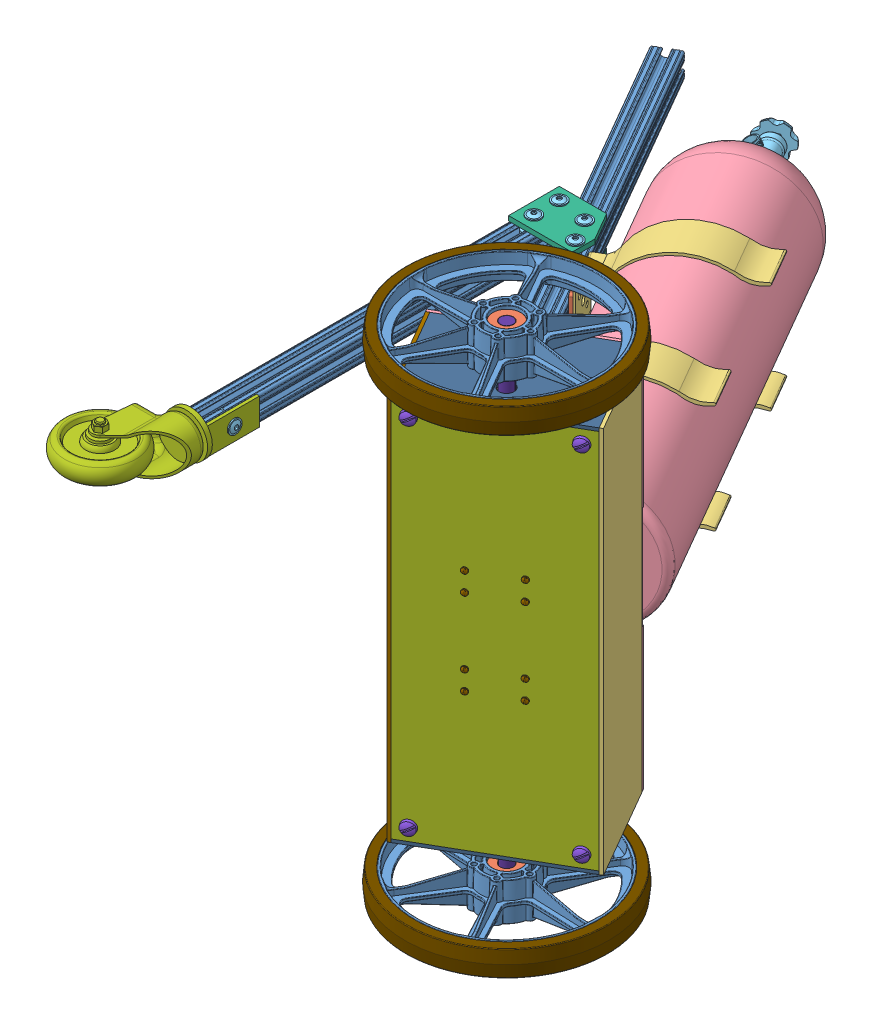
SolidWorks assembly FullAssembly_v3, configuration Default. Lengths in mm.
Overall size (655.19 583.26 804.17).
116 component instances, 27 part files, 137 mates.
Components (placement in the parent):
- 1010 PROFILE-1: 1010 PROFILE [15] at (144.6535 199.9594 480.8949) size (25.4 25.4 381)
- 1010 PROFILE-2: 1010 PROFILE [23.75] at (363.5483 199.9594 443.7256) x (0.86562 0 -0.500701) z (0.500701 0 0.86562) size (25.4 25.4 603.25)
- tankMount_assy-1: tankMount_assy [Default] at (224.6764 199.9594 171.9359) x (0.500701 0 0.86562) z (0 -1 0) size (41.91 148.62 139.7)
  - tankHoler_Mount-1: tankHoler_Mount [Default] at origin size (38.1 3.17 38.1)
  - tankHolder-1: tankHolder [Default] at (19.05 -83.82 0) x (0 0 -1) z (-1 0 0) size (139.7 145.45 41.91)
- tankMount_assy-2: tankMount_assy [Default] at (300.9832 199.9594 303.8564) x (0.500701 0 0.86562) z (0 -1 0) size (41.91 148.62 139.7)
  - tankHoler_Mount-1: tankHoler_Mount [Default] at origin size (38.1 3.17 38.1)
  - tankHolder-1: tankHolder [Default] at (19.05 -83.82 0) x (0 0 -1) z (-1 0 0) size (139.7 145.45 41.91)
- OxTank_Assy-1: OxTank_Assy [Default] at (447.0589 199.9594 392.7938) x (0.86562 0 -0.500701) z (0 1 0) size (133.35 535.03 133.35)
  - M24_OxTank-1: M24_OxTank [Default] at origin size (133.35 486.41 133.35)
  - M24_Valve-1: M24_Valve [Default] at (0 481.33 0) x (-0.429874 0 0.902889) z (-0.902889 0 -0.429874) size (43.69 53.7 33.5)
- 30Deg PN4143-1: 30Deg PN4143 [Default] at (131.9535 217.4346 150.6949) x (0 0 -1) z (1 0 0) size (50.8 4.78 63.5)
- 30Deg PN4143-2: 30Deg PN4143 [Default] at (131.9535 187.2594 150.6949) x (0 0 -1) z (1 0 0) size (50.8 4.78 63.5)
- MotorBox_Assy-1: MotorBox_Assy [Default] at (405.6518 199.9594 541.8792) x (-0.117796 0.990698 0.068137) z (0.500701 0 0.86562) size (541.44 344.28 279.2)
  - 1010 PROFILE-3: 1010 PROFILE [13] at (161.8359 -35.0491 -15.875) x (-0.136082 -0.990698 0) z (0.990698 -0.136082 0) size (25.4 25.4 330.2)
  - MotorBox_Base-1: MotorBox_Base [Default] at (-10.3695 -75.4912 -3.175) x (-0.990698 0.136082 0) z (0.136082 0.990698 0) size (381 3.17 152.4)
  - Motor_Bracket-2: Motor_Bracket [Default] at (-159.2475 -55.0412 -31.75) x (0.136082 0.990698 0) z (-0.990698 0.136082 0) size (88.9 50.8 20.96)
  - Motor_Bracket-3: Motor_Bracket [Default] at (138.5085 -95.9411 -31.75) x (-0.136082 -0.990698 0) z (0.990698 -0.136082 0) size (88.9 50.8 20.96)
  - MotorBox_BackPlate-1: MotorBox_BackPlate [Default] at (0 0 -53.0225) x (0.990698 -0.136082 0) z (0.136082 0.990698 0) size (387.35 106.05 3.17)
  - 1010 PROFILE-5: 1010 PROFILE [4.05] at (-177.8743 11.6136 -3.175) x (0.990698 -0.136082 0) z (0 0 1) size (25.4 25.4 102.87)
  - 1010 PROFILE-6: 1010 PROFILE [4.05] at (174.4178 -36.7773 -3.175) x (0.990698 -0.136082 0) z (0 0 1) size (25.4 25.4 102.87)
  - motorbox_sidePlate-1: motorbox_sidePlate [Default] at (188.7279 -25.9237 0) x (0.990698 -0.136082 0) z (0.136082 0.990698 0) size (3.17 106.05 152.4)
  - motorbox_sidePlate-3: motorbox_sidePlate [Default] at (-191.8733 26.3558 0) x (0.990698 -0.136082 0) z (0.136082 0.990698 0) size (3.17 106.05 152.4)
  - MotorMount_3Dp2-1: MotorMount_3Dp2 [Default] at (17.0936 -79.2635 -3.175) x (-0.136082 -0.990698 0) z (0.990698 -0.136082 0) size (57.15 50.9 30.48)
  - MotorMount_3Dp2-2: MotorMount_3Dp2 [Default] at (-37.8325 -71.7188 -3.175) x (0.136082 0.990698 0) z (-0.990698 0.136082 0) size (57.15 50.9 30.48)
  - 90Deg 2Hole 4108-5: 90Deg 2Hole 4108 [Default] at (-190.2753 0.4978 -55.6714) x (0.990698 -0.136082 0) z (0.136082 0.990698 0) size (25.4 25.4 25.4)
  - 90Deg 2Hole 4108-6: 90Deg 2Hole 4108 [Default] at (186.8188 -25.6615 -55.6714) x (-0.990698 0.136082 0) z (-0.136082 -0.990698 0) size (25.4 25.4 25.4)
  - Motor_Coupler_WheelAssy-1: Motor_Coupler_WheelAssy [Default] at (82.653 -91.6609 -43.1023) x (0.117796 0.857568 -0.500701) z (-0.990698 0.136082 0) size (204.35 204.35 248.71)
    - Motor-1: Motor [Default] at (-2.7115 -11.3995 12.6743) size (45.1 45.1 159.4)
    - Coupler_Assembly-1: Coupler_Assembly [Default] at (-18.5282 -16.0979 -94.9854) x (0.697262 -0.716816 0) z (0 0 1) size (25.52 25.52 28.68)
      - CouplingCenter_59985K630-1: CouplingCenter_59985K630 [59985K63] at (7.6605 14.6137 19.5344) size (25.4 25.4 7.92)
      - halfInCoupling_59985K190-1: halfInCoupling_59985K190 [59985K19] at (7.6605 14.6137 19.4804) size (25.52 25.52 14.06)
      - 10mmCoupling_59985K305-1: 10mmCoupling_59985K305 [59985K305] at (7.6605 14.6137 19.5884) x (0 1 0) z (0 0 -1) size (25.52 25.52 14.06)
    - HalfInch_Shaft-1: HalfInch_Shaft [Default] at (-2.7115 -11.3995 -156.5786) size (12.7 12.7 76.2)
    - 8inWheel_AndyMarkAlternative-1: 8inWheel_AndyMarkAlternative [Default] at (-2.7115 -11.3995 -153.4798) size (204.35 204.35 38.11)
      - 2010 8 tread-1: 2010 8 tread [Default] at (0 0 12.7) size (204.35 204.35 25.4)
      - 2010 8 hub-1: 2010 8 hub [Default] at origin size (190.5 190.5 38.11)
      - r8 bearing-1: r8 bearing [Default] at (0 0 -3.0988) x (-0.726935 0.686706 0) z (0 0 1) size (28.57 28.57 6.35)
      - r8 bearing-2: r8 bearing [Default] at (0 0 28.575) x (0.399336 0.916804 0) z (0 0 -1) size (28.57 28.57 6.35)
  - Motor_Coupler_WheelAssy-2: Motor_Coupler_WheelAssy [Default] at (-104.2482 -65.5549 -20.405) x (0.120301 0.875807 0.467429) z (0.990698 -0.136082 0) size (204.35 204.35 248.71)
    - Motor-1: Motor [Default] at (-2.7115 -11.3995 12.6743) size (45.1 45.1 159.4)
    - Coupler_Assembly-1: Coupler_Assembly [Default] at (-18.5282 -16.0979 -94.9854) x (0.697262 -0.716816 0) z (0 0 1) size (25.52 25.52 28.68)
      - CouplingCenter_59985K630-1: CouplingCenter_59985K630 [59985K63] at (7.6605 14.6137 19.5344) size (25.4 25.4 7.92)
      - halfInCoupling_59985K190-1: halfInCoupling_59985K190 [59985K19] at (7.6605 14.6137 19.4804) size (25.52 25.52 14.06)
      - 10mmCoupling_59985K305-1: 10mmCoupling_59985K305 [59985K305] at (7.6605 14.6137 19.5884) x (0 1 0) z (0 0 -1) size (25.52 25.52 14.06)
    - HalfInch_Shaft-1: HalfInch_Shaft [Default] at (-2.7115 -11.3995 -156.5786) size (12.7 12.7 76.2)
    - 8inWheel_AndyMarkAlternative-1: 8inWheel_AndyMarkAlternative [Default] at (-2.7115 -11.3995 -153.4798) size (204.35 204.35 38.11)
      - 2010 8 tread-1: 2010 8 tread [Default] at (0 0 12.7) size (204.35 204.35 25.4)
      - 2010 8 hub-1: 2010 8 hub [Default] at origin size (190.5 190.5 38.11)
      - r8 bearing-1: r8 bearing [Default] at (0 0 -3.0988) x (-0.726935 0.686706 0) z (0 0 1) size (28.57 28.57 6.35)
      - r8 bearing-2: r8 bearing [Default] at (0 0 28.575) x (0.399336 0.916804 0) z (0 0 -1) size (28.57 28.57 6.35)
  - 1010 PROFILE-7: 1010 PROFILE [4.05] at (157.1353 -162.5959 -3.175) x (-0.136082 -0.990698 0) z (0 0 1) size (25.4 25.4 102.87)
  - 1010 PROFILE-8: 1010 PROFILE [4.05] at (-195.1567 -114.205 -3.175) x (-0.136082 -0.990698 0) z (0 0 1) size (25.4 25.4 102.87)
  - MotorBox_FrontPlate-1: MotorBox_FrontPlate [Default] at (-21.171 -154.1278 -53.0225) x (0.990698 -0.136082 0) z (0.136082 0.990698 0) size (387.35 106.05 3.17)
  - MotorBox_TopPlate-1: MotorBox_TopPlate [Default] at (-10.3695 -75.4912 -109.22) x (-0.990698 0.136082 0) z (0 0 1) size (387.35 158.75 3.17)
  - Tnut_47065T142-1: Tnut_47065T142 [47065T142] at (177.5632 -37.2094 -52.959) x (-0.136082 -0.990698 0) z (0 0 1) size (13.84 15.48 25.4)
  - Tnut_47065T142-2: Tnut_47065T142 [47065T142] at (160.2808 -163.028 -52.959) x (-0.136082 -0.990698 0) z (0 0 1) size (13.84 15.48 25.4)
  - Tnut_47065T142-3: Tnut_47065T142 [47065T142] at (-181.0197 12.0457 -52.959) x (0.136082 0.990698 0) z (0 0 1) size (13.84 15.48 25.4)
  - Tnut_47065T142-4: Tnut_47065T142 [47065T142] at (-198.3022 -113.7729 -52.959) x (0.136082 0.990698 0) z (0 0 1) size (13.84 15.48 25.4)
  - Tnut_47065T142-5: Tnut_47065T142 [47065T142] at (-152.7105 8.1571 -19.05) x (0.136082 0.990698 0) z (-0.990698 0.136082 0) size (13.84 15.48 25.4)
  - Tnut_47065T142-6: Tnut_47065T142 [47065T142] at (-174.7288 11.1815 -41.275) x (-0.136082 -0.990698 0) z (0 0 1) size (13.84 15.48 25.4)
  - Tnut_47065T142-7: Tnut_47065T142 [47065T142] at (171.2723 -36.3453 -41.275) x (-0.135988 -0.990011 0.037224) z (-0.005066 -0.036878 -0.999307) size (13.84 15.48 25.4)
  - Tnut_47065T142-8: Tnut_47065T142 [47065T142] at (149.2541 -33.3208 -19.05) x (0.136082 0.990698 0) z (-0.990698 0.136082 0) size (13.84 15.48 25.4)
- Tbracket_47065T182-1: Tbracket_47065T182 [47065T182] at (335.7146 174.5594 430.4823) x (0 1 0) z (-0.86562 0 0.500701) size (76.2 76.2 4.76)
- 1010 PROFILE-3: 1010 PROFILE [13] at (369.9072 365.0594 454.7189) x (0.86562 0 -0.500701) z (0 1 0) size (25.4 25.4 330.2)
- 90Deg 2Hole 4108-1: 90Deg 2Hole 4108 [Default] at (364.3079 239.7558 470.4032) x (-0.500701 0 -0.86562) z (0.86562 0 -0.500701) size (25.4 25.4 25.4)
- 90Deg 2Hole 4108-2: 90Deg 2Hole 4108 [Default] at (386.2947 160.163 457.6854) x (-0.500701 0 -0.86562) z (-0.86562 0 0.500701) size (25.4 25.4 25.4)
- Caster_2399T600-1: Caster_2399T600 [2399T6] at (143.8597 200.7531 491.2136) x (-1 0 0) z (0 -1 0) size (91.62 149.22 46.44)
- Tbracket_47065T182-2: Tbracket_47065T182 [47065T182] at (361.8239 174.5594 415.3799) x (0 1 0) z (-0.86562 0 0.500701) size (76.2 76.2 4.76)
- 90Deg 2Hole 4108-3: 90Deg 2Hole 4108 [Default] at (375.5065 61.9558 439.0347) x (0.500701 0 0.86562) z (-0.86562 0 0.500701) size (25.4 25.4 25.4)
- 90Deg 2Hole 4108-4: 90Deg 2Hole 4108 [Default] at (353.5198 337.963 451.7525) x (0.500701 0 0.86562) z (0.86562 0 -0.500701) size (25.4 25.4 25.4)
- Tnut_47065T142-1: Tnut_47065T142 [47065T142] at (365.7847 174.5594 457.1035) x (0.085321 0.985374 0.147505) z (0.493378 -0.170404 0.85296) size (13.84 15.48 25.4)
- Tnut_47065T142-2: Tnut_47065T142 [47065T142] at (353.0669 199.9594 435.1168) x (0.180474 0.932781 0.312007) z (0.467044 -0.360443 0.807434) size (13.84 15.48 25.4)
- Tnut_47065T142-3: Tnut_47065T142 [47065T142] at (365.7847 225.3594 457.1035) x (0.427935 0.51917 0.739821) z (0.259949 -0.854671 0.449404) size (13.84 15.48 25.4)
- Tnut_47065T142-4: Tnut_47065T142 [47065T142] at (340.3491 199.9594 413.13) x (0.309252 0.786462 0.534641) z (0.393782 -0.617639 0.680778) size (13.84 15.48 25.4)
- Tnut_47065T142-5: Tnut_47065T142 [47065T142] at (365.7847 199.9594 457.1035) x (0.149627 0.954305 0.258677) z (0.477821 -0.298834 0.826066) size (13.84 15.48 25.4)
- Tnut_47065T142-6: Tnut_47065T142 [47065T142] at (357.1894 196.7844 432.7322) x (-0.837169 0 -0.546944) z (-0.546944 0 0.837169) size (13.84 15.48 25.4)
- Tnut_47065T142-7: Tnut_47065T142 [47065T142] at (368.3175 174.5594 451.9706) x (0.749299 0.500701 -0.433417) z (-0.433417 0.86562 0.250701) size (13.84 15.48 25.4)
- Tnut_47065T142-8: Tnut_47065T142 [47065T142] at (368.3175 225.3594 451.9706) x (0.749299 0.500701 -0.433417) z (-0.433417 0.86562 0.250701) size (13.84 15.48 25.4)
- Tnut_47065T142-9: Tnut_47065T142 [47065T142] at (357.1894 203.1344 432.7322) size (13.84 15.48 25.4)
- Tnut_47065T142-10: Tnut_47065T142 [47065T142] at (348.5941 199.9594 408.3608) x (0.250701 -0.86562 0.433417) z (0.433417 0.500701 0.749299) size (13.84 15.48 25.4)
- Tnut_47065T142-11: Tnut_47065T142 [47065T142] at (361.312 199.9594 430.3476) x (0.250701 -0.86562 0.433417) z (0.433417 0.500701 0.749299) size (13.84 15.48 25.4)
- Tnut_47065T142-12: Tnut_47065T142 [47065T142] at (374.0298 225.3594 452.3344) x (0.250701 -0.86562 0.433417) z (0.433417 0.500701 0.749299) size (13.84 15.48 25.4)
- Tnut_47065T142-13: Tnut_47065T142 [47065T142] at (374.0298 174.5594 452.3344) x (0.250701 -0.86562 0.433417) z (0.433417 0.500701 0.749299) size (13.84 15.48 25.4)
- Tnut_47065T142-14: Tnut_47065T142 [47065T142] at (374.0298 199.9594 452.3344) x (0.201827 -0.915161 0.348922) z (0.458222 0.403089 0.792182) size (13.84 15.48 25.4)
- Tnut_47065T142-15: Tnut_47065T142 [47065T142] at (144.6535 204.7346 112.5949) x (-0.997896 0 0.06484) z (-0.06484 0 -0.997896) size (13.84 15.48 25.4)
- Tnut_47065T142-16: Tnut_47065T142 [47065T142] at (144.6535 204.7346 137.9949) x (-0.997896 0 0.06484) z (-0.06484 0 -0.997896) size (13.84 15.48 25.4)
- Tnut_47065T142-17: Tnut_47065T142 [47065T142] at (174.6966 204.7346 117.2355) x (-0.997896 0 0.06484) z (-0.06484 0 -0.997896) size (13.84 15.48 25.4)
- Tnut_47065T142-18: Tnut_47065T142 [47065T142] at (187.4067 204.7346 139.209) x (-0.997896 0 0.06484) z (-0.06484 0 -0.997896) size (13.84 15.48 25.4)
- Tnut_47065T142-19: Tnut_47065T142 [47065T142] at (144.6535 195.1842 112.5949) x (-0.799944 0 -0.600075) z (-0.600075 0 0.799944) size (13.84 15.48 25.4)
- Tnut_47065T142-20: Tnut_47065T142 [47065T142] at (144.6535 195.1842 137.9949) x (-0.799944 0 -0.600075) z (-0.600075 0 0.799944) size (13.84 15.48 25.4)
- Tnut_47065T142-21: Tnut_47065T142 [47065T142] at (174.6966 195.1842 117.2355) x (-0.799944 0 -0.600075) z (-0.600075 0 0.799944) size (13.84 15.48 25.4)
- Tnut_47065T142-22: Tnut_47065T142 [47065T142] at (187.4067 195.1842 139.209) x (-0.799944 0 -0.600075) z (-0.600075 0 0.799944) size (13.84 15.48 25.4)
- Tnut_47065T142-24: Tnut_47065T142 [47065T142] at (143.8597 196.7844 436.4449) x (0.799944 0 0.600075) z (0.600075 0 -0.799944) size (13.84 15.48 25.4)
- Tnut_47065T142-25: Tnut_47065T142 [47065T142] at (143.8597 196.7844 468.1949) x (0.799944 0 0.600075) z (0.600075 0 -0.799944) size (13.84 15.48 25.4)
- Tnut_47065T142-26: Tnut_47065T142 [47065T142] at (147.8285 200.7531 453.9074) x (0 0.440972 -0.897521) z (0 -0.897521 -0.440972) size (13.84 15.48 25.4)
- Tnut_47065T142-27: Tnut_47065T142 [47065T142] at (382.625 25.3344 476.7057) x (0.997896 0 -0.06484) z (0.06484 0 0.997896) size (13.84 15.48 25.4)
- Tnut_47065T142-28: Tnut_47065T142 [47065T142] at (371.497 47.5594 457.4673) x (-0.862672 -0.08247 0.498995) z (-0.071388 0.996594 0.041293) size (13.84 15.48 25.4)
- Tnut_47065T142-29: Tnut_47065T142 [47065T142] at (382.625 374.5844 476.7057) x (-0.799944 0 -0.600075) z (-0.600075 0 0.799944) size (13.84 15.48 25.4)
- Tnut_47065T142-31: Tnut_47065T142 [47065T142] at (371.497 352.3594 457.4673) x (-0.862672 -0.08247 0.498995) z (-0.071388 0.996594 0.041293) size (13.84 15.48 25.4)
- 0.25-20-94690A542-2: 0.25-20-94690A542 [94690A542] at (471.8924 377.7594 377.3882) x (-0.86562 0 0.500701) z (-0.500701 0 -0.86562) size (13.33 13.33 30.02)
- 0.25-20-94690A542-3: 0.25-20-94690A542 [94690A542] at (361.9586 377.7594 440.9772) x (-0.86562 0 0.500701) z (-0.500701 0 -0.86562) size (13.33 13.33 30.02)
- 0.25-20-94690A542-4: 0.25-20-94690A542 [94690A542] at (361.9586 22.1594 440.9772) x (-0.86562 0 0.500701) z (-0.500701 0 -0.86562) size (13.33 13.33 30.02)
- 0.25-20-94690A542-6: 0.25-20-94690A542 [94690A542] at (471.8924 22.1594 377.3882) x (-0.86562 0 0.500701) z (-0.500701 0 -0.86562) size (13.33 13.33 30.02)
- 0.25-20-94690A542-7: 0.25-20-94690A542 [94690A542] at (526.579 377.7594 471.9313) x (-0.74152 -0.515925 0.428917) z (0.500701 0 0.86562) size (13.33 13.33 30.02)
- 0.25-20-94690A542-8: 0.25-20-94690A542 [94690A542] at (416.6452 377.7594 535.5203) x (-0.74152 -0.515925 0.428917) z (0.500701 0 0.86562) size (13.33 13.33 30.02)
- 0.25-20-94690A542-9: 0.25-20-94690A542 [94690A542] at (526.579 22.1594 471.9313) x (-0.74152 -0.515925 0.428917) z (0.500701 0 0.86562) size (13.33 13.33 30.02)
- 0.25-20-94690A542-12: 0.25-20-94690A542 [94690A542] at (416.6452 22.1594 535.5203) x (-0.74152 -0.515925 0.428917) z (0.500701 0 0.86562) size (13.33 13.33 30.02)
- 4_40-90277A108-1: 4_40-90277A108 [90277A108] at (490.8505 252.4453 492.5977) x (-0.216021 -0.96836 0.124953) z (0.500701 0 0.86562) size (5.97 5.97 11.45)
- 4_40-90277A108-2: 4_40-90277A108 [90277A108] at (452.2637 252.2834 514.9174) x (-0.216021 -0.96836 0.124953) z (0.500701 0 0.86562) size (5.97 5.97 11.45)
- 4_40-90277A108-3: 4_40-90277A108 [90277A108] at (452.2637 233.2334 514.9174) x (-0.216021 -0.96836 0.124953) z (0.500701 0 0.86562) size (5.97 5.97 11.45)
- 4_40-90277A108-4: 4_40-90277A108 [90277A108] at (490.7405 233.2334 492.6613) x (-0.216021 -0.96836 0.124953) z (0.500701 0 0.86562) size (5.97 5.97 11.45)
- 4_40-90277A108-5: 4_40-90277A108 [90277A108] at (490.7405 166.6854 492.6613) x (-0.216021 -0.96836 0.124953) z (0.500701 0 0.86562) size (5.97 5.97 11.45)
- 4_40-90277A108-6: 4_40-90277A108 [90277A108] at (490.7405 147.6354 492.6613) x (-0.216021 -0.96836 0.124953) z (0.500701 0 0.86562) size (5.97 5.97 11.45)
- 4_40-90277A108-8: 4_40-90277A108 [90277A108] at (452.2637 166.6854 514.9174) x (-0.216021 -0.96836 0.124953) z (0.500701 0 0.86562) size (5.97 5.97 11.45)
- 4_40-90277A108-9: 4_40-90277A108 [90277A108] at (452.2637 147.6354 514.9174) x (-0.216021 -0.96836 0.124953) z (0.500701 0 0.86562) size (5.97 5.97 11.45)
Mates (geometry in assembly coordinates):
- Coincident1: coincident aligned: plane of 1010 PROFILE-1 through (144.6535 199.9594 480.8949) normal (0 1 0); plane of 1010 PROFILE-2
- Coincident2: coincident anti-aligned: plane of 1010 PROFILE-2; plane of tankMount_assy-1/tankHoler_Mount-1 through (224.6764 199.9594 171.9359) normal (0 -1 0)
- Coincident3: coincident anti-aligned: plane of 1010 PROFILE-2 through (72.4939 190.409 -84.8188) normal (0.86562 0 -0.500701); plane of tankMount_assy-1/tankHoler_Mount-1 through (221.9281 199.9594 173.5256) normal (-0.86562 0 0.500701)
- Distance1: distance = 279.4 mm aligned: plane of 1010 PROFILE-2 through (60.0209 192.2886 -77.6041) normal (-0.500701 0 -0.86562); plane of tankMount_assy-1/tankHoler_Mount-1 through (212.3897 219.0094 157.0355) normal (-0.500701 0 -0.86562)
- Coincident4: coincident anti-aligned: plane of 1010 PROFILE-2; plane of tankMount_assy-2/tankHoler_Mount-1 through (300.9832 199.9594 303.8564) normal (0 -1 0)
- Coincident5: coincident anti-aligned: plane of 1010 PROFILE-2 through (72.4939 190.409 -84.8188) normal (0.86562 0 -0.500701); plane of tankMount_assy-2/tankHoler_Mount-1 through (298.2349 199.9594 305.4461) normal (-0.86562 0 0.500701)
- Distance2: distance = 431.8 mm aligned: plane of tankMount_assy-2/tankHoler_Mount-1 through (288.6965 219.0094 288.9561) normal (-0.500701 0 -0.86562); plane of 1010 PROFILE-2 through (60.0209 192.2886 -77.6041) normal (-0.500701 0 -0.86562)
- Parallel2: parallel anti-aligned: plane of 1010 PROFILE-2 through (60.0209 192.2886 -77.6041) normal (-0.500701 0 -0.86562); plane of OxTank_Assy-1/M24_OxTank-1 through (447.0589 199.9594 392.7938) normal (0.500701 0 0.86562)
- Coincident7: coincident aligned: plane of 1010 PROFILE-2; plane of OxTank_Assy-1/M24_OxTank-1 through (447.0589 199.9594 392.7938) normal (0 1 0)
- Distance3: distance = 12.7 mm aligned: plane of 30Deg PN4143-1 through (131.9535 217.4346 150.6949) normal (1 0 0); plane of 1010 PROFILE-1 through (144.6535 199.9594 480.8949) normal (1 0 0)
- Coincident9: coincident aligned: plane of 1010 PROFILE-1 through (142.9442 192.2886 99.8949) normal (0 0 -1); plane of 30Deg PN4143-1 through (179.3499 212.6594 99.8949) normal (0 0 -1)
- Coincident10: coincident anti-aligned: plane of 1010 PROFILE-1 through (138.3204 212.6594 99.8949) normal (0 1 0); plane of 30Deg PN4143-1 through (131.9535 212.6594 150.6949) normal (0 -1 0)
- Distance4: distance = 12.7 mm aligned: plane of 1010 PROFILE-1 through (144.6535 199.9594 480.8949) normal (1 0 0); plane of 30Deg PN4143-2 through (131.9535 187.2594 150.6949) normal (1 0 0)
- Coincident12: coincident aligned: plane of 1010 PROFILE-1 through (142.9442 192.2886 99.8949) normal (0 0 -1); plane of 30Deg PN4143-2 through (179.3499 182.4842 99.8949) normal (0 0 -1)
- Coincident13: coincident anti-aligned: plane of 1010 PROFILE-1 through (135.1031 187.2594 99.8949) normal (0 -1 0); plane of 30Deg PN4143-2 through (131.9535 187.2594 150.6949) normal (0 1 0)
- Coincident16: coincident anti-aligned: plane of 1010 PROFILE-2 through (363.5483 199.9594 443.7256) normal (0.86562 0 -0.500701); plane of 30Deg PN4143-2
- Parallel7: parallel anti-aligned: plane of 1010 PROFILE-2 through (363.5483 199.9594 443.7256) normal (0.500701 0 0.86562); plane of MotorBox_Assy-1/MotorBox_BackPlate-1 through (349.8066 6.2844 451.6742) normal (-0.500701 0 -0.86562)
- Coincident25: coincident aligned: plane of 1010 PROFILE-2; plane of OxTank_Assy-1/M24_OxTank-1 through (447.0589 199.9594 392.7938) normal (0 1 0)
- Distance8: distance = 81.915 mm anti-aligned: plane of tankMount_assy-1/tankHoler_Mount-1; plane of OxTank_Assy-1/M24_OxTank-1
- Coincident27: coincident anti-aligned: plane of 1010 PROFILE-2; plane of Tbracket_47065T182-1
- Coincident28: coincident anti-aligned: plane of 1010 PROFILE-2 through (50.5071 209.5098 -72.101) normal (-0.86562 0 0.500701); plane of Tbracket_47065T182-1 through (327.1193 187.2594 406.111) normal (0.86562 0 -0.500701)
- Distance9: distance = 12.7 mm anti-aligned: plane of 1010 PROFILE-3; plane of Tbracket_47065T182-1 through (365.2728 199.9594 472.0712) normal (0.500701 0 0.86562)
- Coincident30: coincident anti-aligned: plane of Tbracket_47065T182-1 through (327.1193 187.2594 406.111) normal (0.86562 0 -0.500701); plane of 1010 PROFILE-3 through (362.0848 34.8594 466.5599) normal (-0.86562 0 0.500701)
- Distance10: distance = 165.1 mm anti-aligned: plane of 1010 PROFILE-3 through (369.9072 365.0594 454.7189) normal (0 1 0); plane of Tbracket_47065T182-1
- Distance11: distance = 25.4 mm aligned: plane of 1010 PROFILE-2 through (362.0688 192.2886 444.5814) normal (0.500701 0 0.86562); plane of Tbracket_47065T182-1 through (365.2728 199.9594 472.0712) normal (0.500701 0 0.86562)
- Coincident33: coincident anti-aligned: plane of 1010 PROFILE-3 through (371.8154 34.8594 438.9437) normal (-0.500701 0 -0.86562); plane of 90Deg 2Hole 4108-1 through (374.5417 238.0594 437.3667) normal (0.500701 0 0.86562)
- Coincident34: coincident anti-aligned: plane of 1010 PROFILE-2 through (69.7675 212.6594 -83.2418) normal (0 1 0); plane of 90Deg 2Hole 4108-1 through (374.5417 212.6594 437.3667) normal (0 -1 0)
- Coincident35: coincident aligned: plane of 1010 PROFILE-3 through (377.7296 34.8594 442.878) normal (0.86562 0 -0.500701); plane of 90Deg 2Hole 4108-1 through (374.5417 234.8844 437.3667) normal (0.86562 0 -0.500701)
- Coincident36: coincident anti-aligned: plane of 1010 PROFILE-2 through (66.9826 187.2594 -81.6309) normal (0 -1 0); plane of 90Deg 2Hole 4108-2 through (352.555 187.2594 450.0845) normal (0 1 0)
- Coincident37: coincident anti-aligned: plane of 1010 PROFILE-3 through (371.8154 34.8594 438.9437) normal (-0.500701 0 -0.86562); plane of 90Deg 2Hole 4108-2 through (352.555 161.8594 450.0845) normal (0.500701 0 0.86562)
- Coincident38: coincident aligned: plane of 1010 PROFILE-3 through (377.7296 34.8594 442.878) normal (0.86562 0 -0.500701); plane of 90Deg 2Hole 4108-2 through (374.5417 165.0344 437.3667) normal (0.86562 0 -0.500701)
- Coincident41: coincident aligned: plane of MotorBox_Assy-1/1010 PROFILE-6 through (370.1883 376.0501 439.8848) normal (-0.500701 0 -0.86562); plane of 1010 PROFILE-3 through (358.0663 34.8594 446.8965) normal (-0.500701 0 -0.86562)
- Coincident42: coincident anti-aligned: plane of MotorBox_Assy-1/1010 PROFILE-6 through (355.2813 365.0594 448.5075) normal (0 -1 0); plane of 1010 PROFILE-3 through (372.2685 365.0594 462.2148) normal (0 1 0)
- Coincident43: coincident aligned: plane of MotorBox_Assy-1/1010 PROFILE-6 through (352.555 371.4263 450.0845) normal (-0.86562 0 0.500701); plane of 1010 PROFILE-3 through (354.132 34.8594 452.8108) normal (-0.86562 0 0.500701)
- Coincident44: coincident anti-aligned: plane of 1010 PROFILE-1 through (142.9442 192.2886 480.8949) normal (0 0 1); plane of Caster_2399T600-1 through (165.6332 200.7531 480.8949) normal (0 0 -1)
- Coincident45: coincident anti-aligned: plane of 1010 PROFILE-1 through (157.3535 206.2925 99.8949) normal (1 0 0); plane of Caster_2399T600-1 through (157.3535 214.2469 428.5074) normal (-1 0 0)
- Coincident46: coincident anti-aligned: plane of 1010 PROFILE-1 through (135.1031 187.2594 99.8949) normal (0 -1 0); plane of Caster_2399T600-1 through (157.3535 187.2594 401.3338) normal (0 1 0)
- Distance15: distance = 96.8375 mm aligned: plane of MotorBox_Assy-1/Motor_Coupler_WheelAssy-1/8inWheel_AndyMarkAlternative-1/2010 8 hub-1; plane of Caster_2399T600-1 through (165.6332 200.7531 480.8949) normal (0 0 -1)
- Coincident47: coincident anti-aligned: plane of 1010 PROFILE-2 through (72.4939 206.2925 -84.8188) normal (0.86562 0 -0.500701); plane of Tbracket_47065T182-2 through (349.1061 187.2594 393.3932) normal (-0.86562 0 0.500701)
- Coincident49: coincident anti-aligned: plane of 1010 PROFILE-2; plane of Tbracket_47065T182-2
- Coincident50: coincident aligned: plane of 1010 PROFILE-3 through (381.7482 34.8594 462.5413) normal (0.500701 0 0.86562); plane of Tbracket_47065T182-2 through (391.382 199.9594 456.9688) normal (0.500701 0 0.86562)
- Coincident51: coincident anti-aligned: plane of 1010 PROFILE-3 through (367.9991 34.8594 470.4942) normal (0.500701 0 0.86562); plane of 90Deg 2Hole 4108-3 through (365.2728 60.2594 472.0712) normal (-0.500701 0 -0.86562)
- Coincident52: coincident anti-aligned: plane of MotorBox_Assy-1/1010 PROFILE-5 through (371.8154 34.8594 438.9437) normal (0 1 0); plane of 90Deg 2Hole 4108-3 through (365.2728 34.8594 472.0712) normal (0 -1 0)
- Coincident53: coincident aligned: plane of 1010 PROFILE-3 through (385.6825 34.8594 456.6271) normal (0.86562 0 -0.500701); plane of 90Deg 2Hole 4108-3 through (387.2595 57.0844 459.3534) normal (0.86562 0 -0.500701)
- Coincident54: coincident anti-aligned: plane of MotorBox_Assy-1/1010 PROFILE-6 through (369.0304 365.0594 440.5546) normal (0 -1 0); plane of 90Deg 2Hole 4108-4 through (387.2595 365.0594 459.3534) normal (0 1 0)
- Coincident55: coincident anti-aligned: plane of 1010 PROFILE-3 through (381.7482 34.8594 462.5413) normal (0.500701 0 0.86562); plane of 90Deg 2Hole 4108-4 through (387.2595 339.6594 459.3534) normal (-0.500701 0 -0.86562)
- Coincident56: coincident aligned: plane of MotorBox_Assy-1/1010 PROFILE-6 through (374.5417 368.209 437.3667) normal (0.86562 0 -0.500701); plane of 90Deg 2Hole 4108-4 through (387.2595 342.8344 459.3534) normal (0.86562 0 -0.500701)
- Concentric1: concentric aligned: circle of Tbracket_47065T182-1; circle of Tnut_47065T142-1
- Concentric2: concentric aligned: circle of Tbracket_47065T182-1; circle of Tnut_47065T142-5
- Concentric3: concentric aligned: circle of Tbracket_47065T182-1; circle of Tnut_47065T142-3
- Concentric4: concentric aligned: circle of Tbracket_47065T182-1; circle of Tnut_47065T142-2
- Concentric5: concentric aligned: circle of Tbracket_47065T182-1; circle of Tnut_47065T142-4
- Coincident74: coincident anti-aligned: plane of Tbracket_47065T182-1 through (322.9968 187.2594 408.4955) normal (-0.86562 0 0.500701); circle of Tnut_47065T142-3
- Coincident75: coincident anti-aligned: plane of Tbracket_47065T182-1 through (322.9968 187.2594 408.4955) normal (-0.86562 0 0.500701); circle of Tnut_47065T142-1
- Coincident76: coincident anti-aligned: plane of Tbracket_47065T182-1 through (322.9968 187.2594 408.4955) normal (-0.86562 0 0.500701); circle of Tnut_47065T142-5
- Coincident77: coincident anti-aligned: plane of Tbracket_47065T182-1 through (322.9968 187.2594 408.4955) normal (-0.86562 0 0.500701); circle of Tnut_47065T142-2
- Coincident78: coincident anti-aligned: plane of Tbracket_47065T182-1 through (322.9968 187.2594 408.4955) normal (-0.86562 0 0.500701); circle of Tnut_47065T142-4
- Concentric7: concentric aligned: circle of 90Deg 2Hole 4108-2; circle of Tnut_47065T142-7
- Coincident79: coincident anti-aligned: plane of 90Deg 2Hole 4108-2 through (350.9652 179.3092 447.3361) normal (-0.500701 0 -0.86562); circle of Tnut_47065T142-7
- Concentric8: concentric aligned: circle of 90Deg 2Hole 4108-2; circle of Tnut_47065T142-6
- Coincident80: coincident anti-aligned: plane of 90Deg 2Hole 4108-2 through (341.4269 184.0844 430.8461) normal (0 -1 0); plane of Tnut_47065T142-6 through (357.1894 184.0844 432.7322) normal (0 1 0)
- Concentric9: concentric aligned: circle of 90Deg 2Hole 4108-1; circle of Tnut_47065T142-9
- Coincident81: coincident anti-aligned: plane of 90Deg 2Hole 4108-1 through (363.4136 215.8344 418.1283) normal (0 1 0); plane of Tnut_47065T142-9 through (357.1894 215.8344 432.7322) normal (0 -1 0)
- Concentric10: concentric aligned: cylinder of 90Deg 2Hole 4108-1 through (350.8305 225.3594 421.7388) axis (0.500701 0 0.86562) radius 3.2639; circle of Tnut_47065T142-8
- Coincident82: coincident anti-aligned: plane of 90Deg 2Hole 4108-1 through (372.952 220.6096 434.6183) normal (-0.500701 0 -0.86562); plane of Tnut_47065T142-8 through (361.9586 225.3594 440.9772) normal (0.500701 0 0.86562)
- Concentric11: concentric anti-aligned: circle of Tbracket_47065T182-2; circle of Tnut_47065T142-10
- Coincident83: coincident anti-aligned: plane of Tbracket_47065T182-2 through (353.2286 187.2594 391.0086) normal (0.86562 0 -0.500701); circle of Tnut_47065T142-10
- Concentric12: concentric anti-aligned: circle of Tbracket_47065T182-2; circle of Tnut_47065T142-11
- Coincident84: coincident anti-aligned: plane of Tbracket_47065T182-2 through (353.2286 187.2594 391.0086) normal (0.86562 0 -0.500701); plane of Tnut_47065T142-11 through (372.3053 199.9594 423.9887) normal (-0.86562 0 0.500701)
- Concentric14: concentric anti-aligned: circle of Tbracket_47065T182-2; circle of Tnut_47065T142-12
- Coincident85: coincident anti-aligned: plane of Tbracket_47065T182-2 through (353.2286 187.2594 391.0086) normal (0.86562 0 -0.500701); plane of Tnut_47065T142-12 through (385.0231 225.3594 445.9755) normal (-0.86562 0 0.500701)
- Concentric15: concentric anti-aligned: circle of Tbracket_47065T182-2; circle of Tnut_47065T142-14
- Concentric16: concentric anti-aligned: circle of Tbracket_47065T182-2; circle of Tnut_47065T142-13
- Coincident86: coincident anti-aligned: plane of Tbracket_47065T182-2 through (353.2286 187.2594 391.0086) normal (0.86562 0 -0.500701); plane of Tnut_47065T142-13 through (385.0231 174.5594 445.9755) normal (-0.86562 0 0.500701)
- Coincident89: coincident anti-aligned: circle of Tbracket_47065T182-2; plane of Tnut_47065T142-14 through (385.0231 199.9594 445.9755) normal (-0.86562 0 0.500701)
- Concentric17: concentric anti-aligned: circle of 30Deg PN4143-1; circle of Tnut_47065T142-15
- Coincident90: coincident anti-aligned: plane of 30Deg PN4143-1 through (131.9535 217.4346 150.6949) normal (0 1 0); plane of Tnut_47065T142-15 through (144.6535 217.4346 112.5949) normal (0 -1 0)
- Concentric18: concentric anti-aligned: circle of 30Deg PN4143-1; circle of Tnut_47065T142-16
- Coincident91: coincident anti-aligned: plane of 30Deg PN4143-1 through (131.9535 217.4346 150.6949) normal (0 1 0); plane of Tnut_47065T142-16 through (144.6535 217.4346 137.9949) normal (0 -1 0)
- Concentric19: concentric anti-aligned: circle of 30Deg PN4143-1; circle of Tnut_47065T142-17
- Coincident92: coincident anti-aligned: plane of 30Deg PN4143-1 through (131.9535 217.4346 150.6949) normal (0 1 0); plane of Tnut_47065T142-17 through (174.6966 217.4346 117.2355) normal (0 -1 0)
- Concentric20: concentric anti-aligned: cylinder of 30Deg PN4143-1 through (187.4067 212.6594 139.209) axis (0 1 0) radius 3.2639; circle of Tnut_47065T142-18
- Coincident93: coincident anti-aligned: plane of 30Deg PN4143-1 through (131.9535 217.4346 150.6949) normal (0 1 0); plane of Tnut_47065T142-18 through (187.4067 217.4346 139.209) normal (0 -1 0)
- Concentric21: concentric aligned: circle of 30Deg PN4143-2; circle of Tnut_47065T142-19
- Coincident94: coincident anti-aligned: plane of 30Deg PN4143-2 through (131.9535 182.4842 150.6949) normal (0 -1 0); plane of Tnut_47065T142-19 through (144.6535 182.4842 112.5949) normal (0 1 0)
- Concentric22: concentric aligned: circle of 30Deg PN4143-2; circle of Tnut_47065T142-20
- Coincident95: coincident anti-aligned: plane of 30Deg PN4143-2 through (131.9535 182.4842 150.6949) normal (0 -1 0); plane of Tnut_47065T142-20 through (144.6535 182.4842 137.9949) normal (0 1 0)
- Concentric23: concentric aligned: circle of 30Deg PN4143-2; circle of Tnut_47065T142-21
- Coincident96: coincident anti-aligned: plane of 30Deg PN4143-2 through (131.9535 182.4842 150.6949) normal (0 -1 0); plane of Tnut_47065T142-21 through (174.6966 182.4842 117.2355) normal (0 1 0)
- Concentric24: concentric aligned: circle of 30Deg PN4143-2; circle of Tnut_47065T142-22
- Coincident97: coincident anti-aligned: plane of 30Deg PN4143-2 through (131.9535 182.4842 150.6949) normal (0 -1 0); plane of Tnut_47065T142-22 through (187.4067 182.4842 139.209) normal (0 1 0)
- Concentric25: concentric anti-aligned: circle of Caster_2399T600-1; circle of Tnut_47065T142-24
- Coincident98: coincident anti-aligned: plane of Caster_2399T600-1 through (157.3535 184.0844 401.3338) normal (0 -1 0); plane of Tnut_47065T142-24 through (143.8597 184.0844 436.4449) normal (0 1 0)
- Concentric26: concentric anti-aligned: circle of Caster_2399T600-1; circle of Tnut_47065T142-25
- Coincident99: coincident anti-aligned: plane of Caster_2399T600-1 through (157.3535 184.0844 401.3338) normal (0 -1 0); plane of Tnut_47065T142-25 through (143.8597 184.0844 468.1949) normal (0 1 0)
- Concentric27: concentric aligned: circle of Caster_2399T600-1; circle of Tnut_47065T142-26
- Coincident100: coincident anti-aligned: plane of Caster_2399T600-1 through (160.5285 214.2469 428.5074) normal (1 0 0); plane of Tnut_47065T142-26 through (160.5285 200.7531 453.9074) normal (-1 0 0)
- Concentric28: concentric aligned: circle of 90Deg 2Hole 4108-3; circle of Tnut_47065T142-27
- Coincident101: coincident anti-aligned: plane of 90Deg 2Hole 4108-3 through (376.4008 38.0344 491.3096) normal (0 1 0); plane of Tnut_47065T142-27 through (382.625 38.0344 476.7057) normal (0 -1 0)
- Concentric29: concentric aligned: circle of 90Deg 2Hole 4108-3; circle of Tnut_47065T142-28
- Coincident102: coincident anti-aligned: plane of 90Deg 2Hole 4108-3 through (366.8625 42.8096 474.8196) normal (0.500701 0 0.86562); plane of Tnut_47065T142-28 through (377.8559 47.5594 468.4607) normal (-0.500701 0 -0.86562)
- Concentric30: concentric aligned: circle of 90Deg 2Hole 4108-4; circle of Tnut_47065T142-29
- Coincident103: coincident anti-aligned: plane of 90Deg 2Hole 4108-4 through (398.3876 361.8844 478.5918) normal (0 -1 0); plane of Tnut_47065T142-29 through (382.625 361.8844 476.7057) normal (0 1 0)
- Concentric31: concentric aligned: circle of 90Deg 2Hole 4108-4; circle of Tnut_47065T142-31
- Coincident104: coincident anti-aligned: plane of 90Deg 2Hole 4108-4 through (388.8492 357.1092 462.1018) normal (0.500701 0 0.86562); plane of Tnut_47065T142-31 through (377.8559 352.3594 468.4607) normal (-0.500701 0 -0.86562)
- Concentric32: concentric anti-aligned: circle of MotorBox_Assy-1/MotorBox_TopPlate-1; circle of 0.25-20-94690A542-2
- Coincident105: coincident anti-aligned: plane of MotorBox_Assy-1/MotorBox_TopPlate-1 through (416.9255 199.9594 409.1827) normal (-0.500701 0 -0.86562); plane of 0.25-20-94690A542-2 through (471.8924 377.7594 377.3882) normal (0.500701 0 0.86562)
- Concentric33: concentric anti-aligned: circle of MotorBox_Assy-1/MotorBox_TopPlate-1; circle of 0.25-20-94690A542-3
- Coincident106: coincident anti-aligned: plane of MotorBox_Assy-1/MotorBox_TopPlate-1 through (416.9255 199.9594 409.1827) normal (-0.500701 0 -0.86562); plane of 0.25-20-94690A542-3 through (361.9586 377.7594 440.9772) normal (0.500701 0 0.86562)
- Concentric34: concentric anti-aligned: circle of MotorBox_Assy-1/MotorBox_TopPlate-1; circle of 0.25-20-94690A542-4
- Coincident107: coincident anti-aligned: plane of MotorBox_Assy-1/MotorBox_TopPlate-1 through (416.9255 199.9594 409.1827) normal (-0.500701 0 -0.86562); plane of 0.25-20-94690A542-4 through (361.9586 22.1594 440.9772) normal (0.500701 0 0.86562)
- Concentric35: concentric anti-aligned: circle of MotorBox_Assy-1/MotorBox_TopPlate-1; circle of 0.25-20-94690A542-6
- Coincident108: coincident anti-aligned: plane of MotorBox_Assy-1/MotorBox_TopPlate-1 through (416.9255 199.9594 409.1827) normal (-0.500701 0 -0.86562); plane of 0.25-20-94690A542-6 through (471.8924 22.1594 377.3882) normal (0.500701 0 0.86562)
- Concentric36: concentric aligned: circle of MotorBox_Assy-1/MotorBox_Base-1; circle of 0.25-20-94690A542-7
- Coincident109: coincident anti-aligned: plane of MotorBox_Assy-1/MotorBox_Base-1 through (471.6121 199.9594 503.7258) normal (0.500701 0 0.86562); plane of 0.25-20-94690A542-7 through (526.579 377.7594 471.9313) normal (-0.500701 0 -0.86562)
- Concentric37: concentric aligned: circle of MotorBox_Assy-1/MotorBox_Base-1; circle of 0.25-20-94690A542-8
- Coincident110: coincident anti-aligned: plane of MotorBox_Assy-1/MotorBox_Base-1 through (471.6121 199.9594 503.7258) normal (0.500701 0 0.86562); plane of 0.25-20-94690A542-8 through (416.6452 377.7594 535.5203) normal (-0.500701 0 -0.86562)
- Concentric38: concentric aligned: circle of MotorBox_Assy-1/MotorBox_Base-1; circle of 0.25-20-94690A542-9
- Coincident111: coincident anti-aligned: plane of MotorBox_Assy-1/MotorBox_Base-1 through (471.6121 199.9594 503.7258) normal (0.500701 0 0.86562); plane of 0.25-20-94690A542-9 through (526.579 22.1594 471.9313) normal (-0.500701 0 -0.86562)
- Concentric39: concentric aligned: circle of MotorBox_Assy-1/MotorBox_Base-1; circle of 0.25-20-94690A542-12
- Coincident112: coincident anti-aligned: plane of MotorBox_Assy-1/MotorBox_Base-1 through (471.6121 199.9594 503.7258) normal (0.500701 0 0.86562); plane of 0.25-20-94690A542-12 through (416.6452 22.1594 535.5203) normal (-0.500701 0 -0.86562)
- Concentric40: concentric anti-aligned: circle of MotorBox_Assy-1/MotorMount_3Dp2-1; circle of 4_40-90277A108-1
- Coincident113: coincident anti-aligned: plane of MotorBox_Assy-1/MotorBox_Base-1 through (471.6121 199.9594 503.7258) normal (0.500701 0 0.86562); circle of 4_40-90277A108-1
- Concentric41: concentric anti-aligned: circle of MotorBox_Assy-1/MotorBox_Base-1; circle of 4_40-90277A108-2
- Coincident114: coincident anti-aligned: plane of MotorBox_Assy-1/MotorBox_Base-1 through (471.6121 199.9594 503.7258) normal (0.500701 0 0.86562); circle of 4_40-90277A108-2
- Concentric42: concentric anti-aligned: circle of MotorBox_Assy-1/MotorBox_Base-1; circle of 4_40-90277A108-3
- Coincident115: coincident anti-aligned: plane of MotorBox_Assy-1/MotorBox_Base-1 through (471.6121 199.9594 503.7258) normal (0.500701 0 0.86562); circle of 4_40-90277A108-3
- Concentric43: concentric anti-aligned: circle of MotorBox_Assy-1/MotorBox_Base-1; circle of 4_40-90277A108-4
- Coincident116: coincident anti-aligned: plane of MotorBox_Assy-1/MotorBox_Base-1 through (471.6121 199.9594 503.7258) normal (0.500701 0 0.86562); circle of 4_40-90277A108-4
- Concentric44: concentric anti-aligned: circle of MotorBox_Assy-1/MotorBox_Base-1; circle of 4_40-90277A108-5
- Coincident117: coincident anti-aligned: plane of MotorBox_Assy-1/MotorBox_Base-1 through (471.6121 199.9594 503.7258) normal (0.500701 0 0.86562); circle of 4_40-90277A108-5
- Concentric45: concentric anti-aligned: circle of MotorBox_Assy-1/MotorBox_Base-1; circle of 4_40-90277A108-6
- Coincident118: coincident anti-aligned: plane of MotorBox_Assy-1/MotorBox_Base-1 through (471.6121 199.9594 503.7258) normal (0.500701 0 0.86562); circle of 4_40-90277A108-6
- Concentric46: concentric anti-aligned: circle of MotorBox_Assy-1/MotorBox_Base-1; circle of 4_40-90277A108-8
- Coincident119: coincident anti-aligned: plane of MotorBox_Assy-1/MotorBox_Base-1 through (471.6121 199.9594 503.7258) normal (0.500701 0 0.86562); circle of 4_40-90277A108-8
- Concentric47: concentric anti-aligned: circle of MotorBox_Assy-1/MotorBox_Base-1; circle of 4_40-90277A108-9
- Coincident120: coincident anti-aligned: plane of MotorBox_Assy-1/MotorBox_Base-1 through (471.6121 199.9594 503.7258) normal (0.500701 0 0.86562); circle of 4_40-90277A108-9
